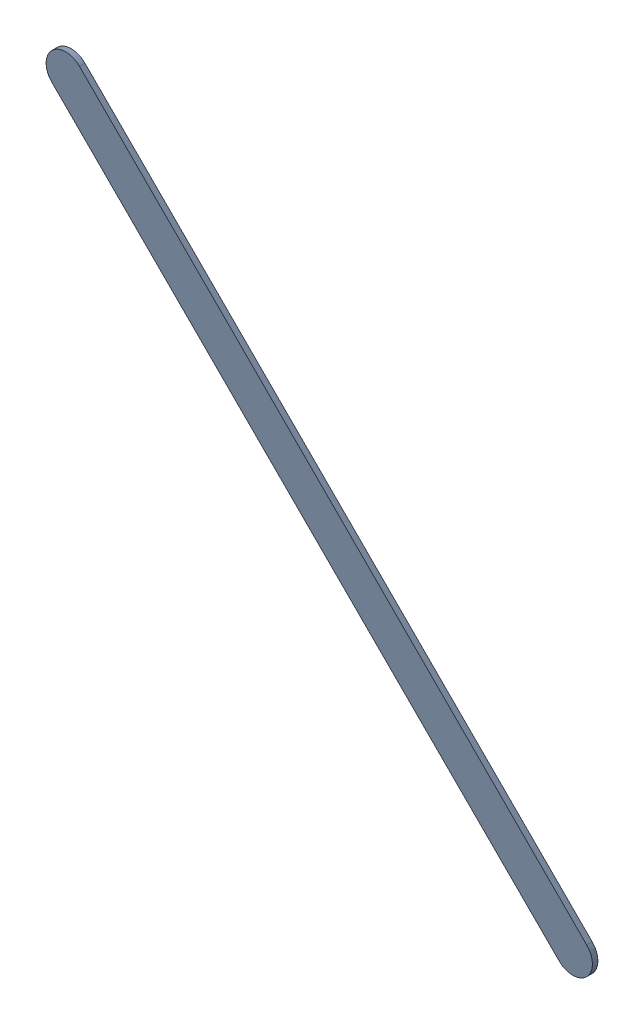
SolidWorks assembly Track (31.1mm,60.8mm)(34.4mm,57.5mm) on Top Layer, configuration Predeterminado. Lengths in mm.
Overall size (3.55 3.55 0.04).
2 component instances, 1 part files, 0 mates.
Components (placement in the parent):
- Track (31.1mm,60.8mm)(34.4mm,57.5mm) on Top Layer-1-1: Track (31.1mm,60.8mm)(34.4mm,57.5mm) on Top Layer-1 [Predeterminado] at (-68.317 -44.187 -0.0457) size (3.55 3.55 0.04)
  - Track (31.1mm,60.8mm)(34.4mm,57.5mm) on Top Layer-Part-1-1: Track (31.1mm,60.8mm)(34.4mm,57.5mm) on Top Layer-Part-1 [Predeterminado] at origin size (3.55 3.55 0.04)
